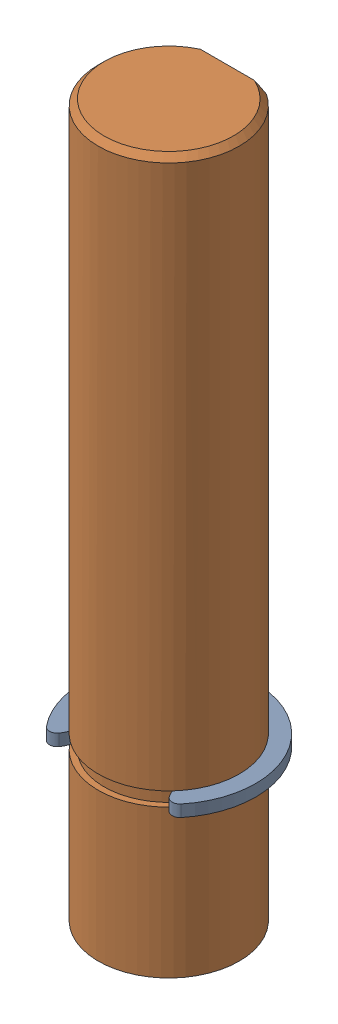
SolidWorks assembly Shaft.stp, configuration Default. Lengths in mm.
Overall size (7.4 30.3 6.7).
2 component instances, 2 part files, 0 mates.
Components (placement in the parent):
- Retaining Ring.stp-1: Retaining Ring.stp [Default] at (0 16.65 0) x (-1 0 0) z (0 -1 0) size (7.4 6.16 0.5)
- Shaft-0.stp-1: Shaft-0.stp [Default] at origin size (6 30.3 6)
